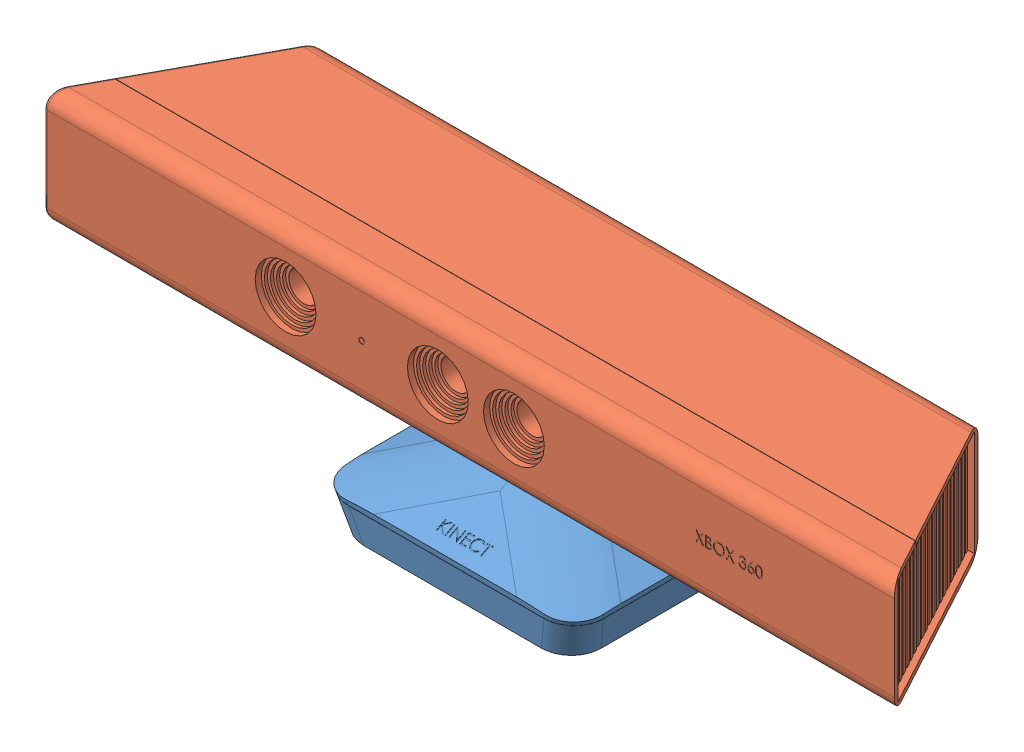
SolidWorks assembly final kinect, configuration Default. Lengths in mm.
Overall size (279.32 72.5 71.02).
2 component instances, 2 part files, 2 mates.
Components (placement in the parent):
- lower part-1: lower part [Default] at (2.1296 -16.1755 0.9636) size (86.05 27.21 71.02)
- kinect upper part-1: kinect upper part [Default] at (2.268 17.8245 -1.5083) size (279.32 38 60)
Mates (geometry in assembly coordinates):
- Concentric1: concentric: sphere of lower part-1; sphere of kinect upper part-1
- Parallel1: parallel anti-aligned: plane of lower part-1 through (-26.5143 -16.6755 23.2804) normal (0 -1 0); plane of kinect upper part-1 through (2.268 55.8245 -1.5083) normal (0 1 0)
